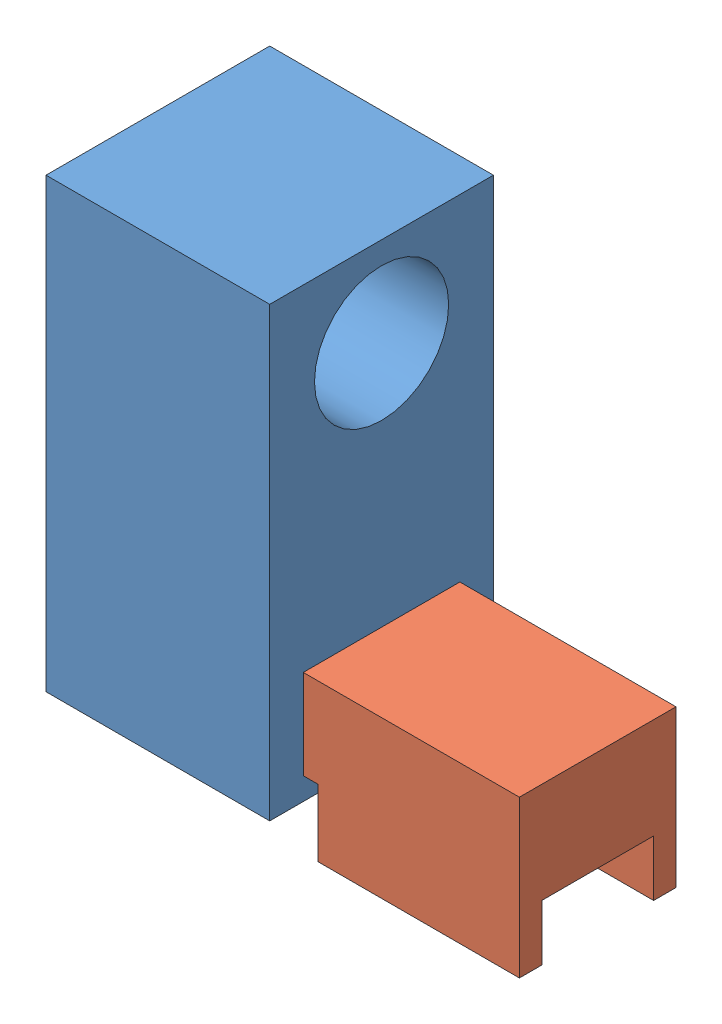
SolidWorks assembly 装配体1, configuration 默认. Lengths in mm.
Overall size (200 220 100).
2 component instances, 2 part files, 2 mates.
Components (placement in the parent):
- 1-2: 1 [默认] at (-85.1145 117.6645 118.5468) size (100 200 100)
- 2-3: 2 [默认] at (-104.7087 6.8167 133.5468) size (200 70 70)
Mates (geometry in assembly coordinates):
- 重合8: coincident anti-aligned: plane of 1-2 through (-143.8774 -2.2324 203.5468) normal (0 1 0); plane of 2-3 through (-37.2707 -2.2324 203.5468) normal (0 -1 0)
- 重合9: coincident aligned: line of 1-2 through (-143.8774 -2.2324 203.5468) axis (1 0 0); line of 2-3 through (-147.2707 -2.2324 203.5468) axis (1 0 0)
